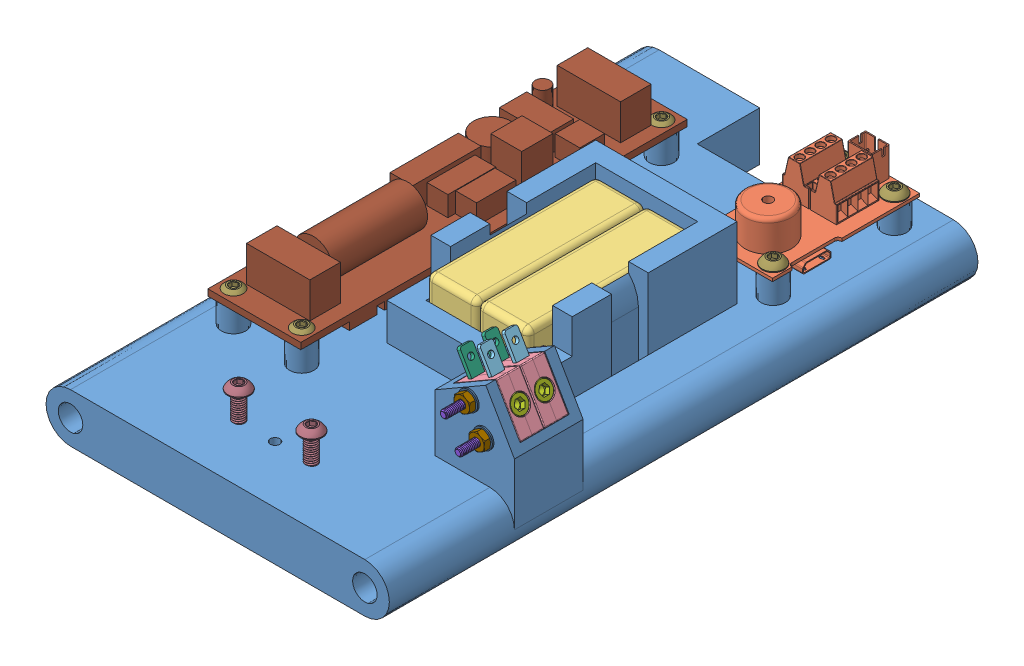
SolidWorks assembly avbay_internals, configuration Default. Lengths in mm.
Overall size (88.9 40.57 152.4).
38 component instances, 14 part files, 47 mates.
Components (placement in the parent):
- avbay_sled-1: avbay_sled [Default] at (48.529 83.6237 42.4096) size (88.9 35.07 152.4)
- easymini-1: easymini [Default] at (73.294 96.3237 67.0476) x (0 0 -1) z (1 0 0) size (38.1 12.14 20.32)
- 2s-battery-1: 2s-battery [Default] at (45.9537 97.9112 116.3236) size (13.21 15.88 43.94)
- 2s-battery-2: 2s-battery [Default] at (59.1617 97.9112 116.3236) size (13.21 15.88 43.94)
- terminalblock-1: terminalblock [Default] at (62.626 89.9737 179.9506) (suppressed, hidden)
- Fingertech_Switch-1: Fingertech_Switch [Default] at (81.6229 102.6936 157.1274) x (0.5 -0.866025 0) z (0.866025 0.5 0) size (19.06 6.61 12.71)
  - Mini_Power_Switch.IGS-1: Mini_Power_Switch.IGS [Default] at origin size (19.06 6.61 12.71)
    - switch half R1.1.IGS-1: switch half R1.1.IGS [Default] at (-0.0319 -2.7572 1.89) size (12.72 4.51 12.71)
    - switch half R1.1.IGS-2: switch half R1.1.IGS [Default] at (-0.0319 3.5928 1.89) x (-1 0 0) z (0 0 1) size (12.72 4.51 12.71)
    - copper tab_through hole.IGS-1: copper tab_through hole.IGS [Default] at (-4.4769 0.4178 4.3948) size (16.52 4.58 1.01)
    - copper tab.IGS-1: copper tab.IGS [Default] at (-4.4769 0.4178 -1.5988) size (16.52 4.58 1.01)
    - SHCS 4-40x375_HX-SHCS 0.112-40x0.375x0.375-S.IGS-1: SHCS 4-40x375_HX-SHCS 0.112-40x0.375x0.375-S.IGS [Default] at (-0.0319 0.4178 8.138) x (0 0 -1) z (1 0 0) size (12.09 6.61 4.66)
- Fingertech_Switch-2: Fingertech_Switch [Default] at (81.6229 102.6936 150.7774) x (0.5 -0.866025 0) z (0.866025 0.5 0) size (19.06 6.61 12.71)
  - Mini_Power_Switch.IGS-1: Mini_Power_Switch.IGS [Default] at origin size (19.06 6.61 12.71)
    - switch half R1.1.IGS-1: switch half R1.1.IGS [Default] at (-0.0319 -2.7572 1.89) size (12.72 4.51 12.71)
    - switch half R1.1.IGS-2: switch half R1.1.IGS [Default] at (-0.0319 3.5928 1.89) x (-1 0 0) z (0 0 1) size (12.72 4.51 12.71)
    - copper tab_through hole.IGS-1: copper tab_through hole.IGS [Default] at (-4.4769 0.4178 4.3948) size (16.52 4.58 1.01)
    - copper tab.IGS-1: copper tab.IGS [Default] at (-4.4769 0.4178 -1.5988) size (16.52 4.58 1.01)
    - SHCS 4-40x375_HX-SHCS 0.112-40x0.375x0.375-S.IGS-1: SHCS 4-40x375_HX-SHCS 0.112-40x0.375x0.375-S.IGS [Default] at (-0.0319 0.4178 8.138) x (0 0 -1) z (1 0 0) size (12.09 6.61 4.66)
- m2_25_screw-1: m2_25_screw [91292A032] at (81.3387 106.9658 155.7446) x (1 0 0) z (0 0 -1) size (3.8 3.8 27.29)
- m2_25_screw-2: m2_25_screw [91292A032] at (85.1487 100.3666 155.7446) x (-1 0 0) z (0 0 -1) size (3.8 3.8 27.29)
- m2_nut-1: m2_nut [90591A265] at (85.1487 100.3666 163.6246) x (1 0 0) z (0 0 -1) size (4 4.62 1.87)
- m2_washer-1: m2_washer [93475A195] at (85.1487 100.3666 144.6446) x (-1 0 0) z (0 0 -1) size (5 5 0.4)
- m2_washer-2: m2_washer [93475A195] at (85.1487 100.3666 162.8246) x (1 0 0) z (0 0 -1) size (5 5 0.4)
- m2_nut-2: m2_nut [90591A265] at (81.3387 106.9658 163.6246) x (1 0 0) z (0 0 -1) size (4 4.62 1.87)
- m2_washer-3: m2_washer [93475A195] at (81.3387 106.9658 162.8246) x (1 0 0) z (0 0 -1) size (5 5 0.4)
- m2_washer-4: m2_washer [93475A195] at (81.3387 106.9658 144.6446) x (1 0 0) z (0 0 -1) size (5 5 0.4)
- rrc3-2: rrc3 [Default] at (13.804 96.3237 162.2246) x (1 0 0) z (0 1 0) size (24.05 100.05 14.25)
- m3_8_screw-9: m3_8_screw [92095A181] at (80.294 98.7611 51.3476) x (1 0 0) z (0 1 0) size (5.7 5.7 9.95)
- m3_8_screw-10: m3_8_screw [92095A181] at (80.294 98.7611 82.7476) x (1 0 0) z (0 1 0) size (5.7 5.7 9.95)
- m3_8_screw-11: m3_8_screw [92095A181] at (66.294 98.7611 82.7476) x (1 0 0) z (0 1 0) size (5.7 5.7 9.95)
- m3_8_screw-12: m3_8_screw [92095A181] at (66.294 98.7611 51.3476) x (1 0 0) z (0 1 0) size (5.7 5.7 9.95)
- m3_8_screw-13: m3_8_screw [92095A181] at (34.454 98.7611 65.8246) x (1 0 0) z (0 1 0) size (5.7 5.7 9.95)
- m3_8_screw-14: m3_8_screw [92095A181] at (16.804 98.7611 65.8246) x (1 0 0) z (0 1 0) size (5.7 5.7 9.95)
- m3_8_screw-15: m3_8_screw [92095A181] at (16.804 98.7611 158.9746) x (1 0 0) z (0 1 0) size (5.7 5.7 9.95)
- m3_8_screw-16: m3_8_screw [92095A181] at (34.454 98.7611 158.9746) x (1 0 0) z (0 1 0) size (5.7 5.7 9.95)
- m3_16_screw-1: m3_16_screw [92095A184] at (39.131 98.6087 179.9506) x (1 0 0) z (0 1 0) size (5.7 5.7 18)
- m3_16_screw-2: m3_16_screw [92095A184] at (57.927 98.6087 179.9506) x (1 0 0) z (0 1 0) size (5.7 5.7 18)
Mates (geometry in assembly coordinates):
- Parallel1: parallel anti-aligned: plane of avbay_sled-1 through (10.429 89.9737 194.8096) normal (0 1 0); plane of easymini-1 through (83.454 96.3237 80.0976) normal (0 -1 0)
- Distance2: distance = 6.35 mm anti-aligned: plane of easymini-1 through (83.454 96.3237 80.0976) normal (0 -1 0); plane of avbay_sled-1 through (10.429 89.9737 194.8096) normal (0 1 0)
- Coincident9: coincident anti-aligned: plane of 2s-battery-1 through (59.1617 97.9112 116.3236) normal (1 0 0); plane of 2s-battery-2 through (59.1617 97.9112 116.3236) normal (-1 0 0)
- Coincident10: coincident aligned: plane of 2s-battery-1 through (59.1617 89.9737 94.3526) normal (0 0 -1); plane of 2s-battery-2 through (72.3697 89.9737 94.3526) normal (0 0 -1)
- Coincident11: coincident aligned: plane of 2s-battery-1 through (59.1617 89.9737 138.2946) normal (0 -1 0); plane of 2s-battery-2 through (72.3697 89.9737 138.2946) normal (0 -1 0)
- Coincident12: coincident anti-aligned: plane of avbay_sled-1 through (10.429 89.9737 194.8096) normal (0 1 0); plane of 2s-battery-2 through (72.3697 89.9737 138.2946) normal (0 -1 0)
- Coincident13: coincident anti-aligned: plane of avbay_sled-1 through (10.429 89.9737 194.8096) normal (0 1 0); plane of terminalblock-1 through (48.529 89.9737 179.9506) normal (0 -1 0)
- Coincident14: coincident: plane of avbay_sled-1 through (48.529 83.6237 42.4096) normal (1 0 0); point of terminalblock-1
- Parallel2: parallel aligned: plane of avbay_sled-1 through (10.429 83.6237 194.8096) normal (0 0 1); plane of terminalblock-1 through (46.751 96.9587 188.4596) normal (0 0 1)
- Coincident16: coincident aligned: line of Fingertech_Switch-1 through (85.1487 100.3666 156.7106) axis (0 0 1); line of Fingertech_Switch-2 through (85.1487 100.3666 150.3606) axis (0 0 1)
- Coincident17: coincident aligned: line of Fingertech_Switch-1 through (81.3387 106.9658 159.8856) axis (0 0 -1); line of Fingertech_Switch-2 through (81.3387 106.9658 153.5356) axis (0 0 -1)
- Coincident18: coincident: point of Fingertech_Switch-1/Mini_Power_Switch.IGS-1/switch half R1.1.IGS-2; point of Fingertech_Switch-2/Mini_Power_Switch.IGS-1/switch half R1.1.IGS-1
- Perpendicular1: perpendicular: plane of avbay_sled-1 through (10.429 83.6237 42.4096) normal (0 0 -1); line of Fingertech_Switch-2 through (85.1487 100.3666 150.3606) axis (0 0 1)
- Distance3: distance = 111.125 mm: point of Fingertech_Switch-2/Mini_Power_Switch.IGS-1/switch half R1.1.IGS-1; plane of avbay_sled-1 through (10.429 83.6237 42.4096) normal (0 0 -1)
- Tangent1: tangent anti-aligned: cylinder of avbay_sled-1 through (86.629 83.6237 194.8096) axis (0 0 -1) radius 3.175; plane of easymini-1 through (83.454 97.1111 68.0976) normal (1 0 0)
- Coincident26: coincident: line of Fingertech_Switch-1 through (87.5337 106.143 156.7096) axis (-0.866025 -0.5 0)
- Distance6: distance = 44.45 mm: point of Fingertech_Switch-1/Mini_Power_Switch.IGS-1/SHCS 4-40x375_HX-SHCS 0.112-40x0.375x0.375-S.IGS-1; line of avbay_sled-1 through (48.529 83.6237 42.4096) axis (0 0 -1)
- Coincident29: coincident anti-aligned: plane of m2_25_screw-2 through (86.9537 100.3666 144.2446) normal (0 0 1); plane of m2_washer-1 through (85.1487 100.3666 144.2446) normal (0 0 -1)
- Concentric5: concentric aligned: cylinder of m2_25_screw-2 through (85.1487 100.3666 169.2446) axis (0 0 1) radius 1; cylinder of m2_washer-1 through (85.1487 100.3666 144.2446) axis (0 0 1) radius 1.1
- Coincident30: coincident anti-aligned: plane of m2_25_screw-1 through (79.5337 106.9658 144.2446) normal (0 0 1); plane of m2_washer-4 through (81.3387 106.9658 144.2446) normal (0 0 -1)
- Concentric6: concentric aligned: cylinder of m2_25_screw-1 through (81.3387 106.9658 169.2446) axis (0 0 1) radius 1; cylinder of m2_washer-4 through (81.3387 106.9658 144.2446) axis (0 0 1) radius 1.1
- Coincident31: coincident anti-aligned: plane of m2_nut-2 through (81.3387 106.9658 162.8246) normal (0 0 -1); plane of m2_washer-3 through (81.3387 106.9658 162.8246) normal (0 0 1)
- Concentric7: concentric aligned: circle of m2_nut-2; circle of m2_washer-3
- Concentric8: concentric aligned: circle of m2_nut-1; circle of m2_washer-2
- Coincident32: coincident anti-aligned: plane of m2_nut-1 through (85.1487 100.3666 162.8246) normal (0 0 -1); plane of m2_washer-2 through (85.1487 100.3666 162.8246) normal (0 0 1)
- Coincident33: coincident anti-aligned: plane of avbay_sled-1 through (86.629 83.6237 144.6446) normal (0 0 -1); plane of m2_washer-1 through (85.1487 100.3666 144.6446) normal (0 0 1)
- Concentric9: concentric aligned: line of avbay_sled-1 through (85.1487 100.3666 144.6446) axis (0 0 1); cylinder of m2_25_screw-2 through (85.1487 100.3666 169.2446) axis (0 0 1) radius 1
- Concentric10: concentric aligned: cylinder of avbay_sled-1 through (81.3387 106.9658 137.0246) axis (0 0 1) radius 1; cylinder of m2_25_screw-1 through (81.3387 106.9658 169.2446) axis (0 0 1) radius 1
- Coincident34: coincident anti-aligned: plane of avbay_sled-1 through (86.629 83.6237 144.6446) normal (0 0 -1); plane of m2_washer-4 through (81.3387 106.9658 144.6446) normal (0 0 1)
- Concentric11: concentric aligned: circle of avbay_sled-1; cylinder of m2_washer-2 through (85.1487 100.3666 162.4246) axis (0 0 1) radius 1.1
- Concentric12: concentric aligned: circle of avbay_sled-1; cylinder of m2_washer-3 through (81.3387 106.9658 162.4246) axis (0 0 1) radius 1.1
- Coincident35: coincident anti-aligned: plane of avbay_sled-1 through (86.629 83.6237 162.4246) normal (0 0 1); plane of m2_washer-3 through (81.3387 106.9658 162.4246) normal (0 0 -1)
- Coincident36: coincident anti-aligned: plane of avbay_sled-1 through (86.629 83.6237 162.4246) normal (0 0 1); plane of m2_washer-2 through (85.1487 100.3666 162.4246) normal (0 0 -1)
- Coincident39: coincident aligned: plane of easymini-1 through (83.454 96.3237 80.0976) normal (0 -1 0); plane of rrc3-2 through (28.204 96.3237 102.4746) normal (0 -1 0)
- Parallel6: parallel anti-aligned: plane of avbay_sled-1 through (10.429 83.6237 42.4096) normal (0 0 -1); plane of rrc3-2 through (13.804 96.3237 162.4246) normal (0 0 1)
- Tangent3: tangent anti-aligned: cylinder of avbay_sled-1 through (10.429 83.6237 194.8096) axis (0 0 -1) radius 3.175; plane of rrc3-2 through (13.604 96.3237 162.2246) normal (-1 0 0)
- Coincident41: coincident aligned: plane of avbay_sled-1 through (86.629 83.6237 162.4246) normal (0 0 1); plane of rrc3-2 through (13.804 96.3237 162.4246) normal (0 0 1)
- Distance8: distance = 6.35 mm anti-aligned: plane of 2s-battery-1 through (59.1617 89.9737 138.2946) normal (0 0 1); plane of avbay_sled-1 through (86.629 83.6237 144.6446) normal (0 0 -1)
- Coincident45: coincident anti-aligned: plane of avbay_sled-1 through (72.3697 104.7205 147.1846) normal (-1 0 0); plane of 2s-battery-2 through (72.3697 97.9112 116.3236) normal (1 0 0)
- Distance9: distance = 3.175 mm anti-aligned: plane of easymini-1 through (63.134 97.1111 86.0976) normal (0 0 1); plane of avbay_sled-1 through (40.8737 176.2343 89.2726) normal (0 0 -1)
- Coincident52: coincident anti-aligned: plane of easymini-1 through (83.454 97.1111 80.0976) normal (0 1 0); plane of m3_8_screw-9 through (83.144 97.1111 51.3476) normal (0 -1 0)
- Concentric17: concentric anti-aligned: cylinder of easymini-1 through (80.294 106.3237 51.3476) axis (0 -1 0) radius 1.65; cylinder of m3_8_screw-9 through (80.294 98.7611 51.3476) axis (0 1 0) radius 2.85
- Coincident53: coincident anti-aligned: plane of terminalblock-1 through (29.733 96.9587 179.9506) normal (0 1 0); plane of m3_16_screw-1 through (41.981 96.9587 179.9506) normal (0 -1 0)
- Concentric18: concentric anti-aligned: circle of terminalblock-1; circle of m3_16_screw-1
- Coincident54: coincident anti-aligned: plane of terminalblock-1 through (48.529 96.9587 179.9506) normal (0 1 0); plane of m3_16_screw-2 through (60.777 96.9587 179.9506) normal (0 -1 0)
- Concentric19: concentric anti-aligned: cylinder of terminalblock-1 through (57.927 96.9587 179.9506) axis (0 -1 0) radius 1.5875; cylinder of m3_16_screw-2 through (57.927 98.6087 179.9506) axis (0 1 0) radius 2.85
- Distance10: distance = 6.35 mm aligned: plane of terminalblock-1 through (65.547 96.9587 188.4596) normal (0 0 1); plane of avbay_sled-1 through (10.429 83.6237 194.8096) normal (0 0 1)
